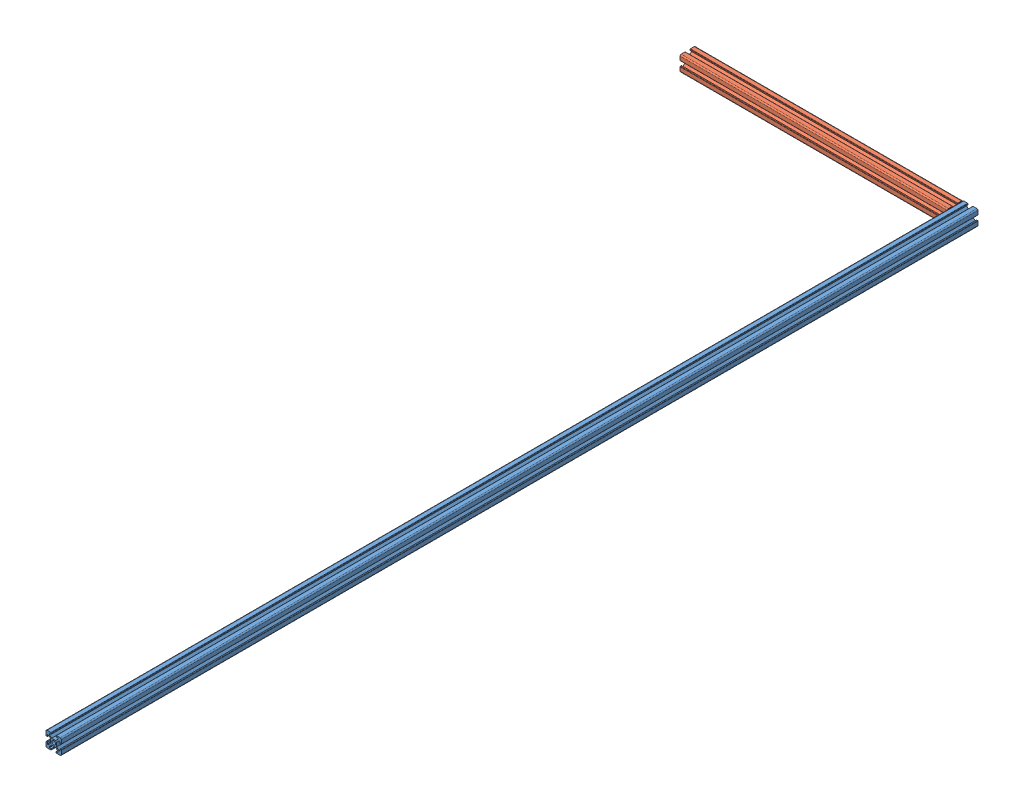
SolidWorks assembly 摄像头支架装配体, configuration 默认. Lengths in mm.
Overall size (370 20 1200).
2 component instances, 2 part files, 3 mates.
Components (placement in the parent):
- 2020型材-1: 2020型材 [默认<按加工>] at (-14.6309 -11.0359 600) size (20 20 1200)
- 2020型材-2-1: 2020型材-2 [默认<按加工>] at (-364.6309 -11.0359 620) x (0 0 -1) z (1 0 0) size (20 20 350)
Mates (geometry in assembly coordinates):
- 重合1: coincident: plane of 2020型材-1 through (-14.6309 -11.0359 1800) normal (-1 0 0); plane of 2020型材-2-1 through (-14.6309 -11.0359 775) normal (1 0 0)
- 重合2: coincident: plane of 2020型材-1 through (-14.6309 8.9641 1800) normal (0 1 0); plane of 2020型材-2-1 through (-14.6309 8.9641 775) normal (0 1 0)
- 重合3: coincident aligned: plane of 2020型材-1 through (-14.6309 -11.0359 600) normal (0 0 -1); plane of 2020型材-2-1 through (-14.6309 -11.0359 600) normal (0 0 -1)
